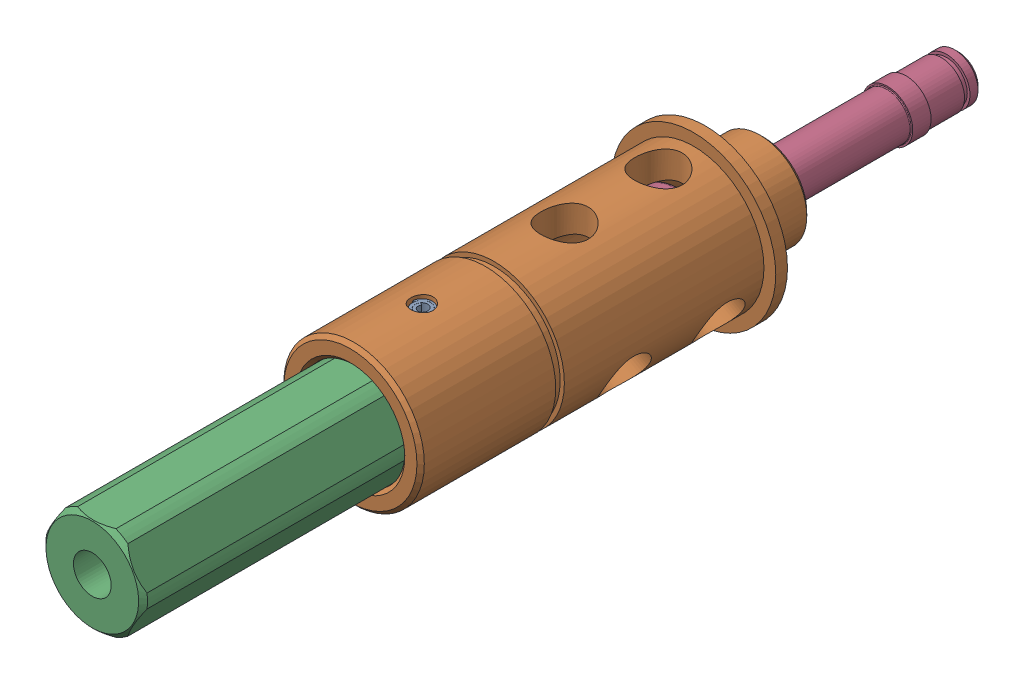
SolidWorks assembly 217-4098-000 Rev2, configuration Default. Lengths in mm.
Overall size (22.23 22.23 117.22).
4 component instances, 4 part files, 0 mates.
Components (placement in the parent):
- 217-4098-005 Rev1_91612A226-1: 217-4098-005 Rev1_91612A226 [Default] at (0 0 46.2661) x (-0.144757 0 0.989467) z (0 -1 0) size (3.02 3.15 18.22)
- 217-4098-003 Rev2-1: 217-4098-003 Rev2 [Default] x (1 0 0) z (0 0 -1) size (22.23 22.23 55.94)
- 217-4098-002 Rev3-1: 217-4098-002 Rev3 [Default] at (0 0 62.9285) x (0 0 1) z (-1 0 0) size (59.88 12.73 14.67)
- 217-4098-004 Rev1-1: 217-4098-004 Rev1 [Default] at (0 0 14.2494) x (0.946095 -0.32389 0) z (0 0 1) size (11.68 11.68 56)
